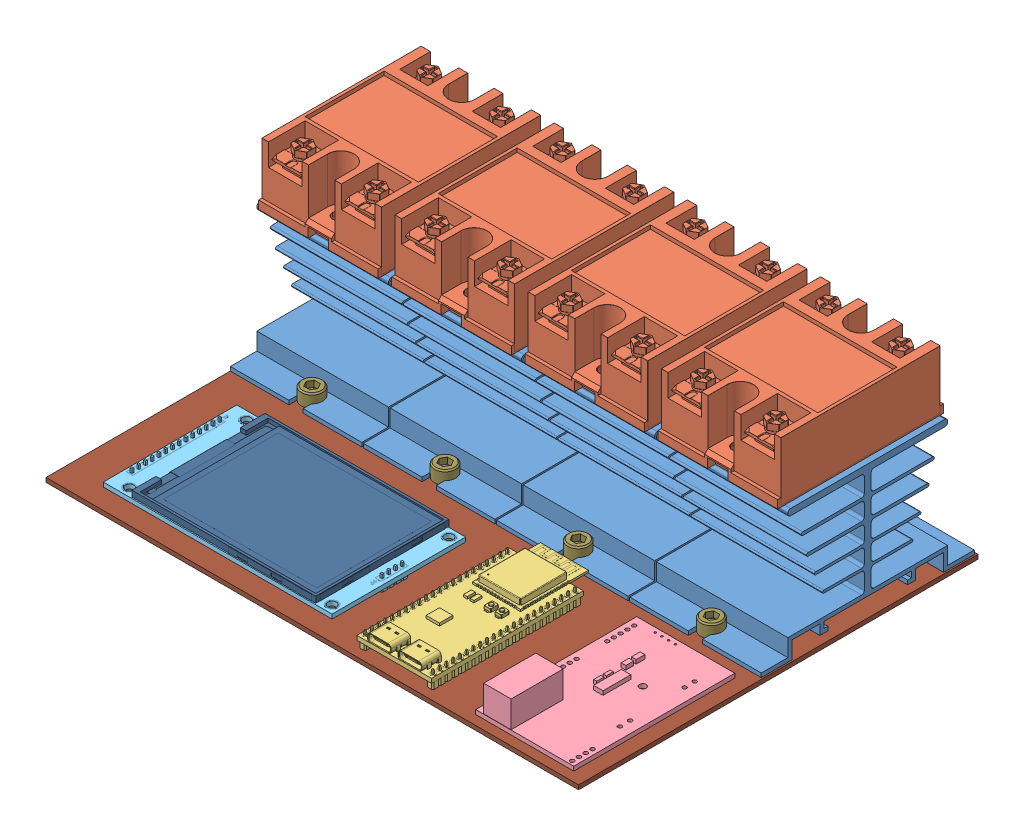
SolidWorks assembly AsicRouter, configuration Défaut. Lengths in mm.
Overall size (418.34 78.43 1217.43).
34 component instances, 12 part files, 23 mates.
Components (placement in the parent):
- heatsink-1: heatsink [Default] at (-29.4265 -6.9364 0) size (49.4 49.5 80)
- SSR-40 DA-1: SSR-40 DA [Défaut] at (-24.4419 43.6316 3.6499) size (44.93 22.58 62.31)
- SSR-40 DA-2: SSR-40 DA [Défaut] at (25.5581 43.6316 3.6499) size (44.93 22.58 62.31)
- SSR-40 DA-3: SSR-40 DA [Défaut] at (75.5581 43.6316 3.6499) size (44.93 22.58 62.31)
- SSR-40 DA-4: SSR-40 DA [Défaut] at (125.5581 43.6316 3.6499) size (44.93 22.58 62.31)
- heatsink-2: heatsink [Default] at (20.5735 -6.9364 0) size (49.4 49.5 80)
- heatsink-3: heatsink [Default] at (70.5735 -6.9364 0) size (49.4 49.5 80)
- heatsink-4: heatsink [Default] at (120.5735 -6.9364 0) size (49.4 49.5 80)
- AI-S3-DEVBOARD-2: AI-S3-DEVBOARD [Défaut] at (83.6228 -11.5255 75.0477) x (1 0 0) z (0 1 0) size (28.01 63.95 13.41)
- jsy-mk-194t-4: jsy-mk-194t [Défaut] at (122.0758 -14.9364 75.3747) x (0 0 -1) z (0 1 0) size (1131.49 412.95 11.6)
- 2.8 TFT Module-1: 2.8 TFT Module [Défaut] at (4.8065 -12.8331 78.5865) x (0 0 -1) z (0 1 0) size (50.19 85.9 11.99)
  - 2.8 TFT Module.stp-1: 2.8 TFT Module.stp [Défaut] at origin size (50.19 85.9 11.99)
    - 2.8 LCD TFT Module - Without Glass.stp-1: 2.8 LCD TFT Module - Without Glass.stp [Défaut] at origin size (50.14 85.9 10.67)
    - 5035000993.stp-1: 5035000993.stp [Défaut] at (3.5564 -3.3047 -2.85) x (0 1 0) z (0 0 -1) size (28.6 21.52 2.95)
    - 0603 Resistor.stp-1: 0603 Resistor.stp [Défaut] at (-2.2311 -3.165 0.0025) x (-1 0 0) z (0 0 -1) size (1.6 0.85 0.56)
    - 0603 Capacitor.stp-1: 0603 Capacitor.stp [Défaut] at (-14.5217 25.6289 0.0025) x (1 0 0) z (0 0 -1) size (1.6 0.84 0.84)
    - 0603 Capacitor.stp-2: 0603 Capacitor.stp [Défaut] at (-2.484 19.738 0.0025) x (-1 0 0) z (0 0 -1) size (1.6 0.84 0.84)
    - 0603 Resistor.stp-2: 0603 Resistor.stp [Défaut] at (-3.8795 -4.7617 0.0025) x (1 0 0) z (0 0 -1) size (1.6 0.85 0.56)
    - 0603 Resistor.stp-3: 0603 Resistor.stp [Défaut] at (-2.3355 -0.9936 0.0025) x (-1 0 0) z (0 0 -1) size (1.6 0.85 0.56)
    - 0603 Resistor.stp-4: 0603 Resistor.stp [Défaut] at (-12.9341 26.6747 0.0025) x (-1 0 0) z (0 0 -1) size (1.6 0.85 0.56)
    - 0603 Resistor.stp-5: 0603 Resistor.stp [Défaut] at (4.5338 19.5922 0.0025) x (-1 0 0) z (0 0 -1) size (1.6 0.85 0.56)
    - 0603 Resistor.stp-6: 0603 Resistor.stp [Défaut] at (4.3803 26.5372 0.0025) x (-1 0 0) z (0 0 -1) size (1.6 0.85 0.56)
    - SOT23-3.stp-1: SOT23-3.stp [Défaut] at (3.6167 23.9432 0.105) x (0.003406 0.999994 0) z (0 0 -1) size (2.87 3.01 1.21)
    - SOT23-3.stp-2: SOT23-3.stp [Défaut] at (-3.3735 23.944 0.105) x (0.999985 -0.005499 0) z (0 0 -1) size (2.87 3.01 1.21)
    - 2.8in TFT(Without Glass)- Tucked Cable.stp-1: 2.8in TFT(Without Glass)- Tucked Cable.stp [Défaut] at (-0.0571 -2.2987 1.6256) x (-1 0 0) z (0 0 1) size (50.11 69.48 2.83)
- mainboard-1: mainboard [Défaut] at (45.8735 -14.9364 34.1966) x (1 0 0) z (0 -1 0) size (200 150 1.6)
- socket head cap screw_ai-1: socket head cap screw_ai [HX-SHCS 0.19-32x0.25x0.25-N] at (-29.4265 -10.1104 34) x (0 -1 0) z (0 0 1) size (11.18 7.94 7.94)
- socket head cap screw_ai-2: socket head cap screw_ai [HX-SHCS 0.19-32x0.25x0.25-N] at (20.5735 -10.1104 34) x (0 -1 0) z (0 0 1) size (11.18 7.94 7.94)
- socket head cap screw_ai-3: socket head cap screw_ai [HX-SHCS 0.19-32x0.25x0.25-N] at (70.5735 -10.1104 34) x (0 -1 0) z (0 0 1) size (11.18 7.94 7.94)
- socket head cap screw_ai-4: socket head cap screw_ai [HX-SHCS 0.19-32x0.25x0.25-N] at (120.5735 -10.1104 34) x (0 -1 0) z (0 0 1) size (11.18 7.94 7.94)
- socket head cap screw_ai-5: socket head cap screw_ai [HX-SHCS 0.19-32x0.25x0.25-N] at (-29.4265 -10.1104 -34) x (0 -1 0) z (0 0 1) size (11.18 7.94 7.94)
- socket head cap screw_ai-6: socket head cap screw_ai [HX-SHCS 0.19-32x0.25x0.25-N] at (20.5735 -10.1104 -34) x (0 -1 0) z (0 0 1) size (11.18 7.94 7.94)
- socket head cap screw_ai-7: socket head cap screw_ai [HX-SHCS 0.19-32x0.25x0.25-N] at (70.5735 -10.1104 -34) x (0 -1 0) z (0 0 1) size (11.18 7.94 7.94)
- socket head cap screw_ai-8: socket head cap screw_ai [HX-SHCS 0.19-32x0.25x0.25-N] at (120.5735 -10.1104 -34) x (0 -1 0) z (0 0 1) size (11.18 7.94 7.94)
Mates (geometry in assembly coordinates):
- Coïncidente1: coincident: plane of heatsink-1 through (36.8548 34.5636 1.3) normal (0 1 0); plane of SSR-40 DA-1 through (-29.4265 34.5636 0.4669) normal (0 -1 0)
- Coaxiale1: concentric: cylinder of heatsink-1 through (-29.4265 34.5636 24) axis (0 1 0) radius 1.65; cylinder of SSR-40 DA-1 through (-29.4265 39.923 24) axis (0 1 0) radius 2.2606
- Coïncidente2: coincident aligned: plane of heatsink-4 through (145.2735 -14.9364 -30) normal (0 -1 0); plane of jsy-mk-194t-2 through (107.8704 -14.9364 81.0932) normal (0 -1 0)
- Coïncidente4: coincident: plane of heatsink-4 through (145.2735 -14.9364 -30) normal (0 -1 0); plane of jsy-mk-194t-4 through (122.0758 -14.9364 75.3747) normal (0 -1 0)
- Coïncidente5: coincident: plane of AI-S3-DEVBOARD-2 through (86.4635 -14.8905 104.4996) normal (0 -1 0); plane of 2.8 TFT Module-1/2.8 TFT Module.stp-1/2.8 LCD TFT Module - Without Glass.stp-1 through (4.8065 -14.8905 78.5865) normal (0 -1 0)
- Coïncidente6: coincident: plane of heatsink-1 through (-4.7265 -14.9364 -30) normal (0 -1 0); plane of mainboard-1 through (45.8735 -14.9364 34.1966) normal (0 1 0)
- Coïncidente7: coincident: plane of heatsink-1 through (-54.1265 -6.9364 0) normal (-1 0 0); plane of mainboard-1 through (-54.1265 -16.5364 -40.8034) normal (-1 0 0)
- Coaxiale21: concentric: cylinder of mainboard-1 through (-29.4265 -24.9364 34) axis (0 1 0) radius 2.5; cylinder of socket head cap screw_ai-1 through (-29.4265 21.6396 34) axis (0 1 0) radius 2.413
- Coïncidente81: coincident: plane of mainboard-1 through (45.8735 -14.9364 34.1966) normal (0 1 0); plane of socket head cap screw_ai-1 through (-25.4578 -14.9364 34) normal (0 -1 0)
- Coaxiale31: concentric: cylinder of mainboard-1 through (20.5735 -24.9364 34) axis (0 1 0) radius 2.5; cylinder of socket head cap screw_ai-2 through (20.5735 21.6396 34) axis (0 1 0) radius 2.413
- Coïncidente91: coincident: plane of mainboard-1 through (45.8735 -14.9364 34.1966) normal (0 1 0); plane of socket head cap screw_ai-2 through (24.5422 -14.9364 34) normal (0 -1 0)
- Coaxiale41: concentric: cylinder of mainboard-1 through (70.5735 -24.9364 34) axis (0 1 0) radius 2.6; cylinder of socket head cap screw_ai-3 through (70.5735 21.6396 34) axis (0 1 0) radius 2.413
- Coïncidente101: coincident: plane of mainboard-1 through (45.8735 -14.9364 34.1966) normal (0 1 0); plane of socket head cap screw_ai-3 through (74.5422 -14.9364 34) normal (0 -1 0)
- Coaxiale51: concentric: cylinder of mainboard-1 through (120.5735 -24.9364 34) axis (0 1 0) radius 2.5; cylinder of socket head cap screw_ai-4 through (120.5735 21.6396 34) axis (0 1 0) radius 2.413
- Coïncidente111: coincident: plane of mainboard-1 through (45.8735 -14.9364 34.1966) normal (0 1 0); plane of socket head cap screw_ai-4 through (124.5422 -14.9364 34) normal (0 -1 0)
- Coaxiale61: concentric: cylinder of mainboard-1 through (-29.4265 -24.9364 -34) axis (0 1 0) radius 2.5; cylinder of socket head cap screw_ai-5 through (-29.4265 21.6396 -34) axis (0 1 0) radius 2.413
- Coïncidente121: coincident: plane of mainboard-1 through (45.8735 -14.9364 34.1966) normal (0 1 0); plane of socket head cap screw_ai-5 through (-25.4578 -14.9364 -34) normal (0 -1 0)
- Coaxiale71: concentric: cylinder of mainboard-1 through (20.5735 -24.9364 -34) axis (0 1 0) radius 2.5; cylinder of socket head cap screw_ai-6 through (20.5735 21.6396 -34) axis (0 1 0) radius 2.413
- Coïncidente131: coincident: plane of mainboard-1 through (45.8735 -14.9364 34.1966) normal (0 1 0); plane of socket head cap screw_ai-6 through (24.5422 -14.9364 -34) normal (0 -1 0)
- Coaxiale81: concentric: cylinder of mainboard-1 through (70.5735 -24.9364 -34) axis (0 1 0) radius 2.5; cylinder of socket head cap screw_ai-7 through (70.5735 21.6396 -34) axis (0 1 0) radius 2.413
- Coïncidente141: coincident: plane of mainboard-1 through (45.8735 -14.9364 34.1966) normal (0 1 0); plane of socket head cap screw_ai-7 through (74.5422 -14.9364 -34) normal (0 -1 0)
- Coaxiale91: concentric: cylinder of mainboard-1 through (120.5735 -24.9364 -34) axis (0 1 0) radius 2.5; cylinder of socket head cap screw_ai-8 through (120.5735 21.6396 -34) axis (0 1 0) radius 2.413
- Coïncidente151: coincident: plane of mainboard-1 through (45.8735 -14.9364 34.1966) normal (0 1 0); plane of socket head cap screw_ai-8 through (124.5422 -14.9364 -34) normal (0 -1 0)
